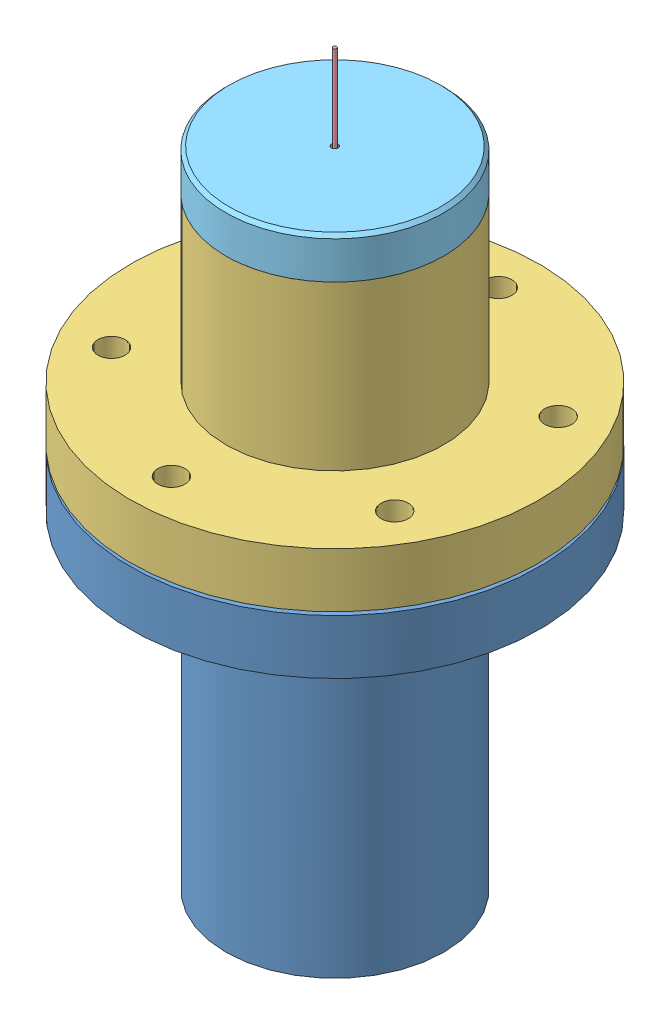
SolidWorks assembly Complete System, configuration Default. Lengths in mm.
Overall size (60.94 84.95 60.94).
10 component instances, 7 part files, 2 mates.
Components (placement in the parent):
- Photoacoustic Chamber-1: Photoacoustic Chamber [Default] at (6.1517 -7.671 23.0428) size (60.94 70.25 60.94)
  - Photoacoustic Chamber Bottom-1: Photoacoustic Chamber Bottom [Default] at (11.1535 29.7627 42.8133) size (47.62 44.45 47.62)
  - Membrane-1: Membrane [Default] at (11.1535 43.0131 42.8133) x (0.993843 0 -0.110796) z (0.110796 0 0.993843) size (31.75 0.4 31.75)
  - Photoacoustic Chamber Top-1: Photoacoustic Chamber Top [Default] at (2.0504 48.2894 46.0916) x (0.940852 0 -0.338819) z (0.338819 0 0.940852) size (47.62 25.4 47.62)
  - Sapphire Fiber-1: Sapphire Fiber [Default] at (11.1535 4.9131 42.8133) x (-0.718309 0 0.695724) z (-0.695724 0 -0.718309) size (0.42 38.1 0.42)
- Probe Head-1: Probe Head [Default] at (20.8595 72.3928 44.4203) x (-0.998491 0 0.054918) z (0.054918 0 0.998491) size (25.4 39.6 25.4)
  - Cell Cap-1: Cell Cap [Default] at (4.7262 6.4914 21.2084) size (25.4 15.88 25.4)
  - Conical Cavity-1: Conical Cavity [Default] at (4.7262 35.0664 21.2084) x (-0.837169 0 -0.546944) z (-0.546944 0 0.837169) (suppressed, hidden)
  - Sapphire Fiber-1: Sapphire Fiber [Default] at (4.7262 -3.4456 21.2084) x (-0.705945 0 -0.708266) z (0.708266 0 -0.705945) size (0.42 38.1 0.42)
  - Polyimide Cylinder-1: Polyimide Cylinder [Default] at (4.7262 31.1544 21.2084) x (0.958365 0 -0.285547) z (0.285547 0 0.958365) size (0.62 5 0.62) (hidden)
Mates (geometry in assembly coordinates):
- Concentric1: concentric: cylinder of Photoacoustic Chamber-1/Photoacoustic Chamber Top-1 through (17.3052 42.0889 65.8562) axis (0 1 0) radius 12.7; cylinder of Probe Head-1/Cell Cap-1 through (17.3052 61.1389 65.8562) axis (0 -1 0) radius 9.525
- Coincident1: coincident: plane of Photoacoustic Chamber-1/Photoacoustic Chamber Top-1 through (5.3564 61.1389 70.1592) normal (0 1 0); plane of Probe Head-1/Cell Cap-1 through (17.3052 61.1389 65.8562) normal (0 -1 0)
